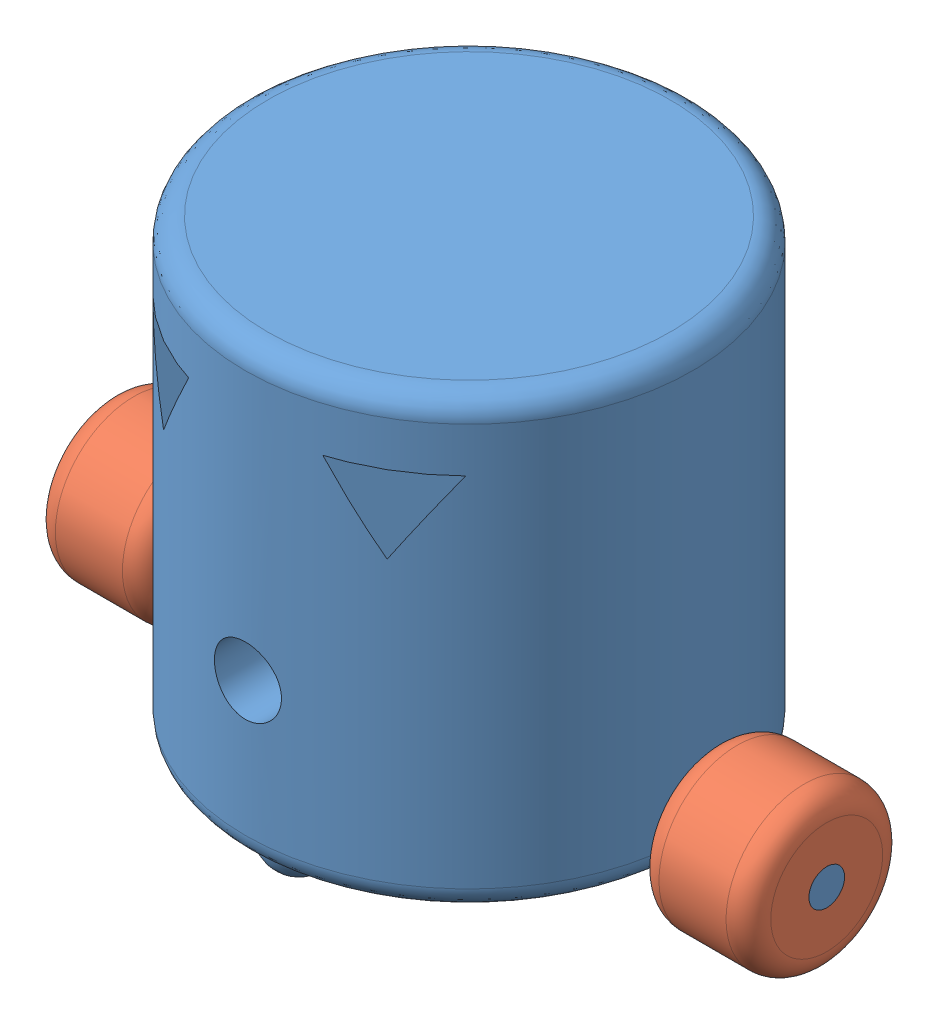
SolidWorks assembly Assemblage1, configuration Défaut. Lengths in mm.
Overall size (160 114.2 100).
3 component instances, 2 part files, 4 mates.
Components (placement in the parent):
- baseBottleBot-1: baseBottleBot [Défaut] at (-183.0645 -27.6044 360) size (160 107.4 100)
- wheelBottleBot-1: wheelBottleBot [Défaut] at (-128.0645 -17.6044 360) x (1 0 0) z (0 0.87664 0.481147) size (25 35 35)
- wheelBottleBot-2: wheelBottleBot [Défaut] at (-263.0645 -17.6044 360) x (1 0 0) z (0 0.543315 0.839529) size (25 35 35)
Mates (geometry in assembly coordinates):
- Coaxiale1: concentric: cylinder of assembly; cylinder of assembly; cylinder of baseBottleBot-1 through (-103.0645 -17.6044 360) axis (-1 0 0) radius 4; cylinder of wheelBottleBot-1 through (-103.0645 -17.6044 360) axis (-1 0 0) radius 4
- Coïncidente1: coincident: plane of assembly; plane of assembly; plane of baseBottleBot-1 through (-103.0645 -17.6044 360) normal (1 0 0); plane of wheelBottleBot-1 through (-103.0645 -17.6044 360) normal (1 0 0)
- Coaxiale2: concentric: cylinder of assembly; cylinder of assembly; cylinder of baseBottleBot-1 through (-263.0645 -17.6044 360) axis (1 0 0) radius 4; cylinder of wheelBottleBot-2 through (-238.0645 -17.6044 360) axis (-1 0 0) radius 4
- Coïncidente2: coincident: plane of assembly; plane of assembly; plane of baseBottleBot-1 through (-263.0645 -17.6044 360) normal (-1 0 0); plane of wheelBottleBot-2 through (-263.0645 -17.6044 360) normal (-1 0 0)
